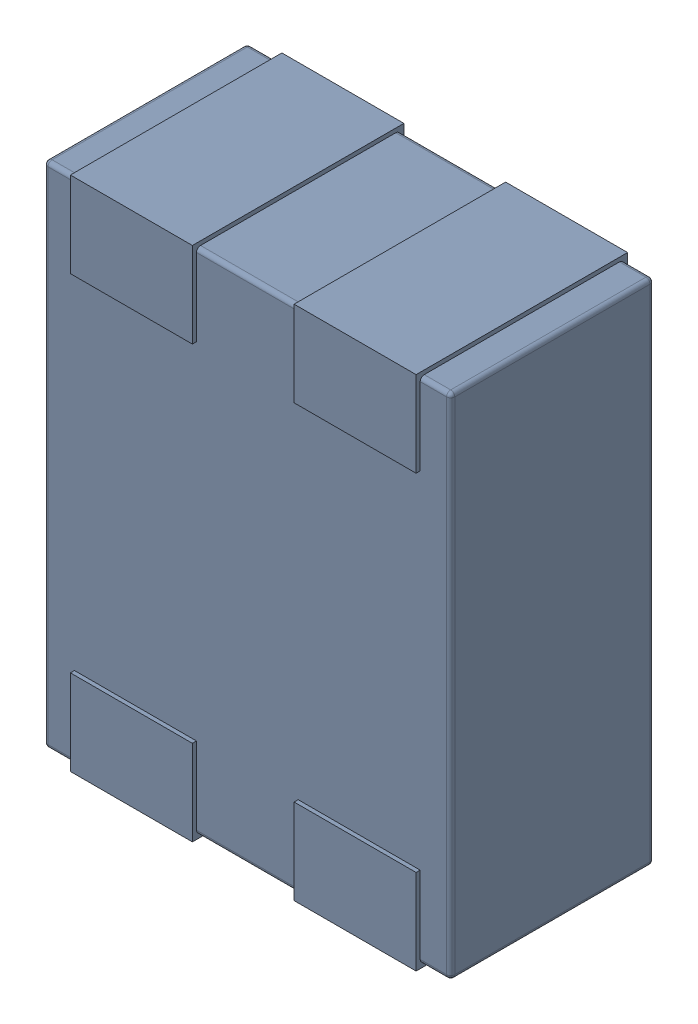
SolidWorks assembly L2, configuration Défaut. Lengths in mm.
Overall size (1 1.27 0.52).
4 component instances, 1 part files, 0 mates.
Components (placement in the parent):
- MCZ1210DH900L2TA0G-1: MCZ1210DH900L2TA0G [Défaut] at (64.6562 -33.8195 -1.6) x (-1 0 0) z (0 0 1) size (1 1.27 0.52)
  - 3D_PCB1_2021-12-30 (1).step-1: 3D_PCB1_2021-12-30 (1).step [Défaut] at origin size (1 1.27 0.52)
    - a3ec64f90eb5404ebd79eca0046a794a.step-1: a3ec64f90eb5404ebd79eca0046a794a.step [Défaut] at (5.0419 -6.8961 1.6) size (1 1.27 0.52)
      - SOLID.step_650-1: SOLID.step_650 [Défaut] at origin size (1 1.27 0.52)
